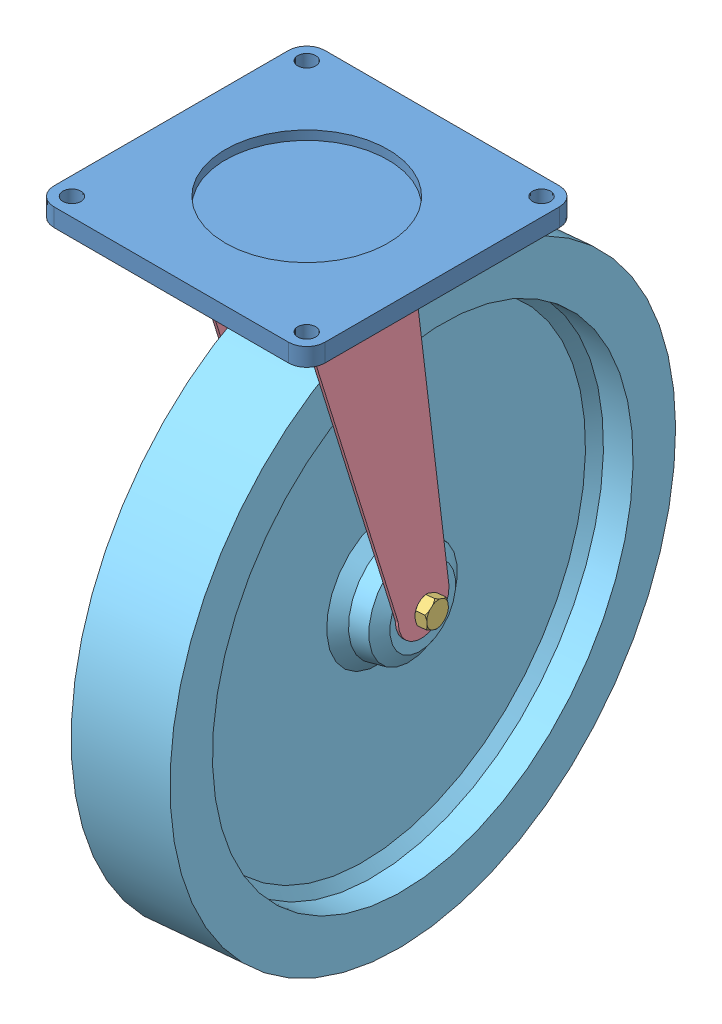
SolidWorks assembly The Goddamn wheel, configuration Default. Lengths in mm.
Overall size (30 82.48 82.21).
5 component instances, 5 part files, 7 mates.
Components (placement in the parent):
- Base Thingy-1: Base Thingy [Default] at (9.5829 17.3189 24.1087) size (30 8 30)
- caster wheel 2part-1: caster wheel 2part [Default] at (253.0962 -67.4948 162.6729) x (-0.096676 -0.221664 -0.970319) z (-0.021976 0.975123 -0.220572) size (99.59 167.11 16.36)
- caster wheel 5part-1: caster wheel 5part [Default] at (-73.5263 -91.826 81.8558) x (-0.080491 0 -0.996755) z (0.996755 0 -0.080491) size (2.93 3.03 16.36)
- Pointy Thingy-1: Pointy Thingy [Default] at (9.5829 14.3189 24.1087) x (-0.099143 0 -0.995073) z (-0.995073 0 0.099143) size (20.12 39.25 18)
- Wheel of Fortune-1: Wheel of Fortune [Default] at (8.7661 -22.3501 15.9104) x (-0.995073 0 0.099143) z (-0.091638 0.381646 -0.919755) size (10 62.5 62.5)
Mates (geometry in assembly coordinates):
- Concentric7: concentric: circle of Base Thingy-1; circle of Pointy Thingy-1
- Coincident1: coincident: circle of Base Thingy-1; circle of Pointy Thingy-1
- Coincident2: coincident: circle of Pointy Thingy-1; circle of Wheel of Fortune-1
- Concentric9: concentric: cylinder of caster wheel 5part-1 through (-1.0055 -22.3501 16.884) axis (0.995073 0 -0.099143) radius 0.9; cylinder of Wheel of Fortune-1 through (3.7907 -22.3501 16.4061) axis (0.995073 0 -0.099143) radius 0.9
- Coincident3: coincident: plane of caster wheel 5part-1 through (14.04 -22.3501 15.3849) normal (-0.995073 0 0.099143); plane of Pointy Thingy-1 through (14.0663 -21.7864 15.6488) normal (0.995073 0 -0.099143)
- Concentric12: concentric: cylinder of caster wheel 2part-1 through (3.4922 -22.3501 16.4358) axis (-0.995073 0 0.099143) radius 0.9; cylinder of caster wheel 5part-1 through (-1.0055 -22.3501 16.884) axis (0.995073 0 -0.099143) radius 0.9
- Coincident4: coincident: plane of caster wheel 2part-1 through (3.4922 -22.3501 16.4358) normal (0.995073 0 -0.099143); plane of Pointy Thingy-1 through (3.5185 -21.7864 16.6997) normal (-0.995073 0 0.099143)
